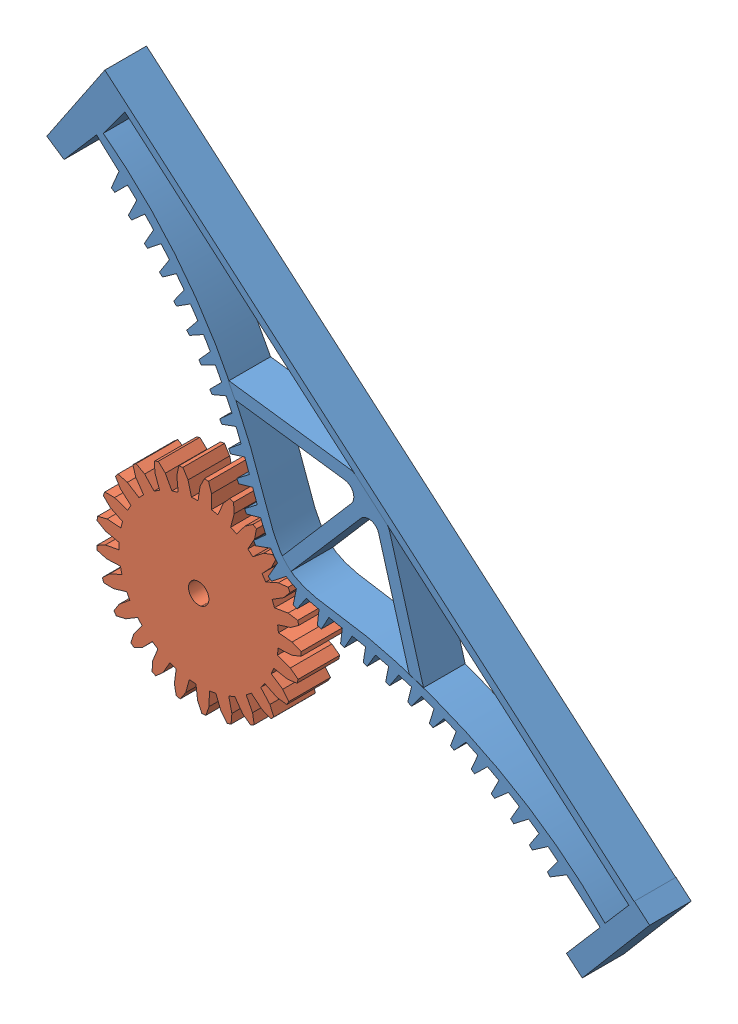
SolidWorks assembly progressive steering, configuration Default. Lengths in mm.
Overall size (147.14 133.68 25.16).
2 component instances, 2 part files, 2 mates.
Components (placement in the parent):
- progressive steering rack-1: progressive steering rack [Default] at (20.9639 133.169 116.748) size (147.14 133.68 10.16)
- elipsed gear-1: elipsed gear [Default] at (4.7265 44.1146 126.908) x (-0.493243 -0.869891 0) z (0 0 -1) size (50.1 50.1 25.16)
Mates (geometry in assembly coordinates):
- Coincident2: coincident aligned: plane of Lucien's idea-1 through (20.9639 133.169 116.748) normal (0 0 -1); plane of elipsed gear-1 through (4.7265 44.1146 116.748) normal (0 0 -1)
- Tangent2: tangent: circle of assembly; curve of progressive steering rack-1; circle of elipsed gear-1
